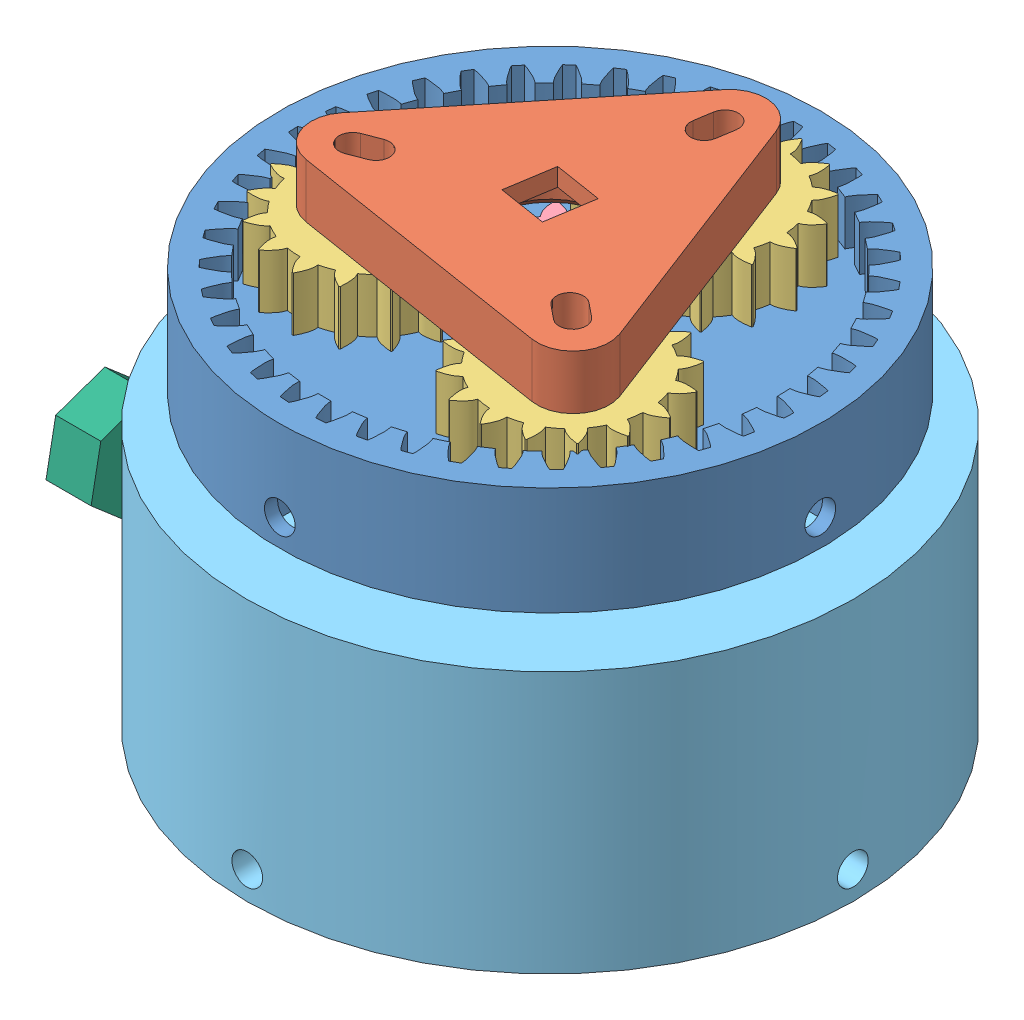
SolidWorks assembly Assem2, configuration Default. Lengths in mm.
Overall size (106.7 70.56 85.34).
14 component instances, 6 part files, 40 mates.
Components (placement in the parent):
- Planetary Gear Box 2.0, RING-1: Planetary Gear Box 2.0, RING [Default] at origin size (85.09 15.24 85.09)
- Planetary Gear Box 2.0, Coupling-1: Planetary Gear Box 2.0, Coupling [Default] at (0 12.7 0) x (0.272802 0 -0.96207) z (0.96207 0 0.272802) size (48.44 7.62 43.31)
- Planetary Gear Box 2.0, PLANETS-5: Planetary Gear Box 2.0, PLANETS [Default] at (5.02 5.08 19.8842) x (0.391039 0 0.920374) z (-0.920374 0 0.391039) size (26.67 7.62 26.67)
- Planetary Gear Box 2.0, PLANETS-6: Planetary Gear Box 2.0, PLANETS [Default] at (-19.7302 5.08 -5.5946) x (0.388319 0 0.921525) z (-0.921525 0 0.388319) size (26.67 7.62 26.67)
- Planetary Gear Box 2.0, PLANETS-7: Planetary Gear Box 2.0, PLANETS [Default] at (14.7102 5.08 -14.2895) x (0.388537 0 0.921433) z (-0.921433 0 0.388537) size (26.67 7.62 26.67)
- Planetary Gear Box 2.0, SUN-1: Planetary Gear Box 2.0, SUN [Default] at (0 12.7 0) x (-0.451789 0 -0.892125) z (-0.892125 0 0.451789) size (18.98 7.62 18.72)
- Planetary Gear Box 2.0, SLEEVE-1: Planetary Gear Box 2.0, SLEEVE [Default] at (0 -3.937 0) size (85.34 36.83 85.34)
- Planetary Gear Box 2.0, RING-2: Planetary Gear Box 2.0, RING [Default] at (0 40.64 0) size (85.09 15.24 85.09)
- Planetary Gear Box 2.0, Coupling-2: Planetary Gear Box 2.0, Coupling [Default] at (0 53.34 0) x (0.987656 0 0.156636) z (-0.156636 0 0.987656) size (48.44 7.62 43.31)
- Planetary Gear Box 2.0, PLANETS-8: Planetary Gear Box 2.0, PLANETS [Default] at (-17.7089 45.72 6.7936) x (-0.873184 0 0.48739) z (-0.48739 0 -0.873184) size (26.67 7.62 26.67)
- Planetary Gear Box 2.0, SUN-2: Planetary Gear Box 2.0, SUN [Default] at (0 53.34 0) x (-0.272802 0 0.96207) z (0.96207 0 0.272802) size (18.98 7.62 18.72)
- Planetary Gear Box 2.0, PLANETS-9: Planetary Gear Box 2.0, PLANETS [Default] at (2.971 45.72 -18.7332) x (-0.933528 0 0.358505) z (-0.358505 0 -0.933528) size (26.67 7.62 26.67)
- Planetary Gear Box 2.0, PLANETS-10: Planetary Gear Box 2.0, PLANETS [Default] at (14.7379 45.72 11.9395) x (-0.665112 0 0.746743) z (-0.746743 0 -0.665112) size (26.67 7.62 26.67)
- Screw-1: Screw [Default] at (-44.9787 0 0) x (0 -0.757584 0.652738) z (0 -0.652738 -0.757584) size (12.7 19.05 14.66)
Mates (geometry in assembly coordinates):
- Concentric1: concentric anti-aligned: cylinder of Planetary Gear Box 2.0, RING-1 through (0 -3.81 0) axis (0 1 0) radius 6.35; cylinder of Planetary Gear Box 2.0, Coupling-1 through (0 17.78 0) axis (0 -1 0) radius 8.128
- Slot1: slot anti-aligned: cylinder of Planetary Gear Box 2.0, PLANETS-5 through (5.02 5.08 19.8842) axis (0 1 0) radius 1.905; plane of Planetary Gear Box 2.0, Coupling-1 through (-1.847 20.32 0.4663) normal (0.969578 0 -0.244782); cylinder of Planetary Gear Box 2.0, Coupling-1 through (4.6428 20.32 18.3903) axis (0 -1 0) radius 1.905
- Distance1: distance = 0 mm anti-aligned: plane of Planetary Gear Box 2.0, Coupling-1 through (0 12.7 0) normal (0 -1 0); plane of Planetary Gear Box 2.0, PLANETS-5 through (5.02 12.7 19.8842) normal (0 1 0)
- Slot2: slot anti-aligned: cylinder of Planetary Gear Box 2.0, PLANETS-6 through (-19.7302 5.08 -5.5946) axis (0 1 0) radius 1.905; cylinder of Planetary Gear Box 2.0, Coupling-1 through (-20.6915 20.32 -5.8672) axis (0 -1 0) radius 1.905; cylinder of Planetary Gear Box 2.0, Coupling-1 through (-18.2479 20.32 -5.1743) axis (0 -1 0) radius 1.905
- Distance2: distance = 0 mm anti-aligned: plane of Planetary Gear Box 2.0, PLANETS-6 through (-19.7302 12.7 -5.5946) normal (0 1 0); plane of Planetary Gear Box 2.0, Coupling-1 through (0 12.7 0) normal (0 -1 0)
- Slot3: slot anti-aligned: cylinder of Planetary Gear Box 2.0, PLANETS-7 through (14.7102 5.08 -14.2895) axis (0 1 0) radius 1.905; cylinder of Planetary Gear Box 2.0, Coupling-1 through (13.605 20.32 -13.216) axis (0 -1 0) radius 1.905; cylinder of Planetary Gear Box 2.0, Coupling-1 through (15.4269 20.32 -14.9858) axis (0 -1 0) radius 1.905
- Distance3: distance = 0 mm anti-aligned: plane of Planetary Gear Box 2.0, PLANETS-7 through (14.7102 12.7 -14.2895) normal (0 1 0); plane of Planetary Gear Box 2.0, Coupling-1 through (0 12.7 0) normal (0 -1 0)
- Distance4: distance = 0 mm anti-aligned: plane of Planetary Gear Box 2.0, PLANETS-7 through (14.7102 5.08 -14.2895) normal (0 -1 0); plane of Planetary Gear Box 2.0, RING-1 through (0 5.08 0) normal (0 1 0)
- GearMate2: gear = 21.59 : 63.5 mm: circle of Planetary Gear Box 2.0, RING-1; circle of Planetary Gear Box 2.0, PLANETS-5
- GearMate3: gear = 63.5 : 21.59 mm: circle of Planetary Gear Box 2.0, PLANETS-7; circle of Planetary Gear Box 2.0, RING-1
- GearMate4: gear = 63.5 : 21.59 mm: circle of Planetary Gear Box 2.0, PLANETS-6; circle of Planetary Gear Box 2.0, RING-1
- Distance5: distance = 0 mm anti-aligned: plane of Planetary Gear Box 2.0, SUN-1 through (0 5.08 0) normal (0 -1 0); plane of Planetary Gear Box 2.0, RING-1 through (0 5.08 0) normal (0 1 0)
- Concentric2: concentric anti-aligned: cylinder of Planetary Gear Box 2.0, RING-1 through (0 -3.81 0) axis (0 1 0) radius 6.35; cylinder of Planetary Gear Box 2.0, SUN-1 through (0 12.7 0) axis (0 -1 0) radius 1.778
- GearMate5: gear = 21.59 : 13.97 mm: circle of Planetary Gear Box 2.0, SUN-1; circle of Planetary Gear Box 2.0, PLANETS-5
- Concentric3: concentric aligned: cylinder of Planetary Gear Box 2.0, RING-1 through (0 5.08 0) axis (0 -1 0) radius 38.1; cylinder of Planetary Gear Box 2.0, SLEEVE-1 through (0 25.273 0) axis (0 -1 0) radius 38.862
- Concentric4: concentric anti-aligned: cylinder of Planetary Gear Box 2.0, RING-1 through (0 0 38.101) axis (0 0 -1) radius 2.159; cylinder of Planetary Gear Box 2.0, SLEEVE-1 through (0 0 -42.672) axis (0 0 1) radius 2.159
- Distance6: distance = 22.352 mm: point of Planetary Gear Box 2.0, PLANETS-5; point of Planetary Gear Box 2.0, RING-1
- Distance7: distance = 22.352 mm: point of Planetary Gear Box 2.0, PLANETS-6; point of Planetary Gear Box 2.0, RING-1
- Distance8: distance = 22.352 mm: point of Planetary Gear Box 2.0, PLANETS-7; point of Planetary Gear Box 2.0, RING-1
- Concentric5: concentric aligned: cylinder of Planetary Gear Box 2.0, RING-1 through (0 5.08 0) axis (0 -1 0) radius 38.1; cylinder of Planetary Gear Box 2.0, RING-2 through (0 45.72 0) axis (0 -1 0) radius 38.1
- Distance9: distance = 25.4 mm anti-aligned: plane of Planetary Gear Box 2.0, RING-2 through (0 36.83 0) normal (0 -1 0); plane of Planetary Gear Box 2.0, RING-1 through (0 11.43 0) normal (0 1 0)
- Coincident2: coincident aligned: plane of Planetary Gear Box 2.0, RING-1 through (0 0 0) normal (0 0 1); plane of Planetary Gear Box 2.0, RING-2 through (0 40.64 0) normal (0 0 1)
- Slot4: slot anti-aligned: cylinder of Planetary Gear Box 2.0, PLANETS-8 through (-17.7089 45.72 6.7936) axis (0 1 0) radius 1.905; plane of Planetary Gear Box 2.0, Coupling-2 through (-0.6823 60.96 -1.7786) normal (0.358177 0 0.933654); cylinder of Planetary Gear Box 2.0, Coupling-2 through (-17.7089 60.96 6.7936) axis (0 -1 0) radius 1.905
- Distance10: distance = 0 mm anti-aligned: plane of Planetary Gear Box 2.0, PLANETS-8 through (-17.7089 53.34 6.7936) normal (0 1 0); plane of Planetary Gear Box 2.0, Coupling-2 through (0 53.34 0) normal (0 -1 0)
- Concentric6: concentric anti-aligned: cylinder of Planetary Gear Box 2.0, RING-2 through (0 36.83 0) axis (0 1 0) radius 6.35; cylinder of Planetary Gear Box 2.0, Coupling-2 through (0 58.42 0) axis (0 -1 0) radius 8.128
- Coincident3: coincident anti-aligned: plane of Planetary Gear Box 2.0, RING-2 through (0 45.72 0) normal (0 1 0); plane of Planetary Gear Box 2.0, PLANETS-8 through (-17.7089 45.72 6.7936) normal (0 -1 0)
- Concentric7: concentric anti-aligned: cylinder of Planetary Gear Box 2.0, RING-2 through (0 36.83 0) axis (0 1 0) radius 6.35; cylinder of Planetary Gear Box 2.0, SUN-2 through (0 53.34 0) axis (0 -1 0) radius 1.778
- Coincident7: coincident anti-aligned: plane of Planetary Gear Box 2.0, RING-2 through (0 45.72 0) normal (0 1 0); plane of Planetary Gear Box 2.0, SUN-2 through (0 45.72 0) normal (0 -1 0)
- Coincident8: coincident aligned: plane of Planetary Gear Box 2.0, Coupling-1 through (0 12.7 0) normal (0.96207 0 0.272802); plane of Planetary Gear Box 2.0, SUN-2 through (0 53.34 0) normal (0.96207 0 0.272802)
- Slot5: slot anti-aligned: cylinder of Planetary Gear Box 2.0, PLANETS-9 through (2.971 45.72 -18.7331) axis (0 1 0) radius 1.905; cylinder of Planetary Gear Box 2.0, Coupling-2 through (3.3688 60.96 -21.2418) axis (0 -1 0) radius 1.905; cylinder of Planetary Gear Box 2.0, Coupling-2 through (2.971 60.96 -18.7332) axis (0 -1 0) radius 1.905
- Distance14: distance = 0 mm anti-aligned: plane of Planetary Gear Box 2.0, PLANETS-9 through (2.971 45.72 -18.7332) normal (0 -1 0); plane of Planetary Gear Box 2.0, RING-2 through (0 45.72 0) normal (0 1 0)
- Coincident11: coincident anti-aligned: plane of Planetary Gear Box 2.0, RING-2 through (0 45.72 0) normal (0 1 0); plane of Planetary Gear Box 2.0, PLANETS-10 through (14.7379 45.72 11.9395) normal (0 -1 0)
- Slot6: slot anti-aligned: cylinder of Planetary Gear Box 2.0, Coupling-2 through (16.7115 60.96 13.5384) axis (0 -1 0) radius 1.905; cylinder of Planetary Gear Box 2.0, PLANETS-10 through (14.7379 45.72 11.9395) axis (0 1 0) radius 1.905; cylinder of Planetary Gear Box 2.0, Coupling-2 through (14.7379 60.96 11.9395) axis (0 -1 0) radius 1.905
- GearMate6: gear = 13.97 : 21.59 mm: circle of Planetary Gear Box 2.0, PLANETS-9; circle of Planetary Gear Box 2.0, SUN-2
- GearMate7: gear = 69.85 : 21.59 mm: circle of Planetary Gear Box 2.0, PLANETS-9; circle of Planetary Gear Box 2.0, RING-2
- GearMate8: gear = 69.85 : 21.59 mm: circle of Planetary Gear Box 2.0, PLANETS-8; circle of Planetary Gear Box 2.0, RING-2
- GearMate9: gear = 69.85 : 21.59 mm: circle of Planetary Gear Box 2.0, PLANETS-10; circle of Planetary Gear Box 2.0, RING-2
- Concentric10: concentric anti-aligned: cylinder of Planetary Gear Box 2.0, SLEEVE-1 through (42.672 0 0) axis (-1 0 0) radius 2.159; cylinder of Screw-1 through (-57.6787 0 0) axis (1 0 0) radius 2.159
- LimitDistance1: limit distance = 12.5937 mm anti-aligned: plane of Screw-1 through (-44.9787 0 0) normal (1 0 0); plane of Planetary Gear Box 2.0, RING-1 through (-32.385 3.81 -3.683) normal (-1 0 0)
- Screw1: screw = 10 aligned: cylinder of Planetary Gear Box 2.0, RING-1 through (-38.101 0 0) axis (1 0 0) radius 2.159; cylinder of Screw-1 through (-57.6787 0 0) axis (1 0 0) radius 2.159
